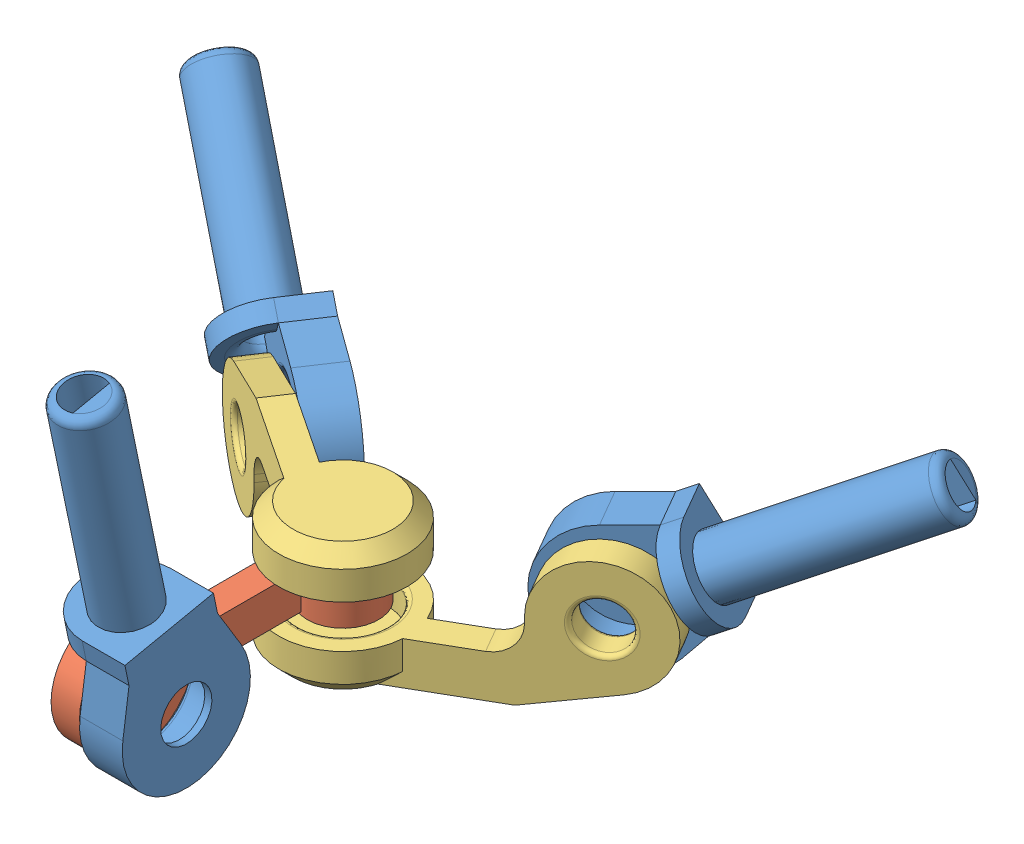
SolidWorks assembly Class3_joint, configuration 默认. Lengths in mm.
Overall size (61.1 28.13 43.93).
6 component instances, 3 part files, 16 mates.
Components (placement in the parent):
- joint_bearing_central-1: joint_bearing_central [默认] at (-46.5752 45.1549 14.651) x (0 -0.203723 0.979029) z (1 0 0) size (9 25 6.17)
- mid_ear-1: mid_ear [默认] at (-46.5752 23.5849 -3.5253) size (5 8 20.5)
- side_ear-1: side_ear [默认] at (-46.5752 26.5849 -3.5253) x (0.554314 0 -0.832308) z (-0.832308 0 -0.554314) size (9 9.5 22.5)
- side_ear-2: side_ear [默认] at (-46.5752 23.5849 -3.5253) x (-0.5 0 -0.866025) z (0.866025 0 -0.5) size (9 9.5 22.5)
- joint_bearing_central-2: joint_bearing_central [默认] at (-73.0039 34.3349 -21.1267) x (0.416154 0.866025 0.277157) z (0.554314 0 -0.832308) size (9 25 6.17)
- joint_bearing_central-3: joint_bearing_central [默认] at (-19.0758 36.3349 -19.4021) x (0.433013 -0.866025 -0.25) z (-0.5 0 -0.866025) size (9 25 6.17)
Mates (geometry in assembly coordinates):
- 同心3: concentric anti-aligned: cylinder of joint_bearing_central-1 through (-44.0752 25.0849 10.4747) axis (-1 0 0) radius 3.15; cylinder of mid_ear-1 through (-49.0762 25.0849 10.4747) axis (1 0 0) radius 1.65
- 距离4: distance = 0.5 mm anti-aligned: plane of joint_bearing_central-1 through (-46.5752 25.0849 10.4747) normal (-1 0 0); plane of mid_ear-1 through (-47.0752 26.3849 -6.0273) normal (1 0 0)
- 同心1: concentric aligned: cylinder of mid_ear-1 through (-46.5752 26.5849 -3.5253) axis (0 -1 0) radius 1.65; cylinder of side_ear-1 through (-46.5752 28.5849 -3.5253) axis (0 -1 0) radius 3.15
- 重合2: coincident anti-aligned: plane of mid_ear-1 through (-46.5752 26.5849 -3.5253) normal (0 1 0); plane of side_ear-1 through (-46.5752 26.5849 -3.5253) normal (0 -1 0)
- 同心2: concentric anti-aligned: cylinder of mid_ear-1 through (-46.5752 26.5849 -3.5253) axis (0 -1 0) radius 1.65; cylinder of side_ear-2 through (-46.5752 21.5849 -3.5253) axis (0 1 0) radius 3.15
- 重合3: coincident anti-aligned: plane of mid_ear-1 through (-46.5752 23.5849 -3.5253) normal (0 -1 0); plane of side_ear-2 through (-46.5752 23.5849 -3.5253) normal (0 1 0)
- 同心5: concentric anti-aligned: cylinder of side_ear-1 through (-59.6133 24.0849 -9.205) axis (0.554314 0 -0.832308) radius 1.65; cylinder of joint_bearing_central-2 through (-56.8417 24.0849 -13.3665) axis (-0.554314 0 0.832308) radius 3.15
- 同心6: concentric anti-aligned: cylinder of side_ear-1 through (-59.6133 24.0849 -9.205) axis (0.554314 0 -0.832308) radius 1.65; cylinder of joint_bearing_central-2 through (-56.8417 24.0849 -13.3665) axis (-0.554314 0 0.832308) radius 3.15
- 距离2: distance = 0.5 mm anti-aligned: plane of side_ear-1 through (-46.8523 26.5849 -3.1092) normal (0.554314 0 -0.832308); plane of joint_bearing_central-2 through (-58.2275 24.0849 -11.2857) normal (-0.554314 0 0.832308)
- 同心4: concentric anti-aligned: cylinder of side_ear-2 through (-33.2008 26.0849 -8.3603) axis (-0.5 0 -0.866025) radius 1.65; cylinder of joint_bearing_central-3 through (-35.7008 26.0849 -12.6904) axis (0.5 0 0.866025) radius 3.15
- 距离3: distance = 0.5 mm anti-aligned: plane of side_ear-2 through (-46.3252 23.5849 -3.0923) normal (-0.5 0 -0.866025); plane of joint_bearing_central-3 through (-34.4508 26.0849 -10.5253) normal (0.5 0 0.866025)
- 角度4: planar angle = 2.094395 rad aligned: plane of side_ear-2 through (-37.531 26.0849 -5.8603) normal (0.5 0 0.866025); plane of mid_ear-1 through (-49.0752 28.0849 -6.0273) normal (-1 0 0)
- 角度5: planar angle = 2.094395 rad anti-aligned: plane of mid_ear-1 through (-49.0752 28.0849 -6.0273) normal (-1 0 0); plane of joint_bearing_central-2 through (-54.066 26.0849 -8.5142) normal (-0.554314 0 0.832308)
- 角度6: planar angle = 1.047198 rad aligned: plane of side_ear-1 through (-46.5752 31.5849 -3.5253) normal (0 1 0); plane of joint_bearing_central-3 through (-30.9564 31.7845 -1.517) normal (0.75 0.5 -0.433013)
- 角度7: planar angle = 2.094395 rad anti-aligned: plane of joint_bearing_central-2 through (-64.9329 26.2852 -4.279) normal (-0.7208 0.5 -0.48005); plane of side_ear-1 through (-46.5752 31.5849 -3.5253) normal (0 1 0)
- 角度8: planar angle = 2.094395 rad anti-aligned: plane of joint_bearing_central-1 through (-56.1239 32.5079 3.5682) normal (0 0.979029 0.203723); plane of side_ear-1 through (-46.5752 31.5849 -3.5253) normal (0 1 0)
